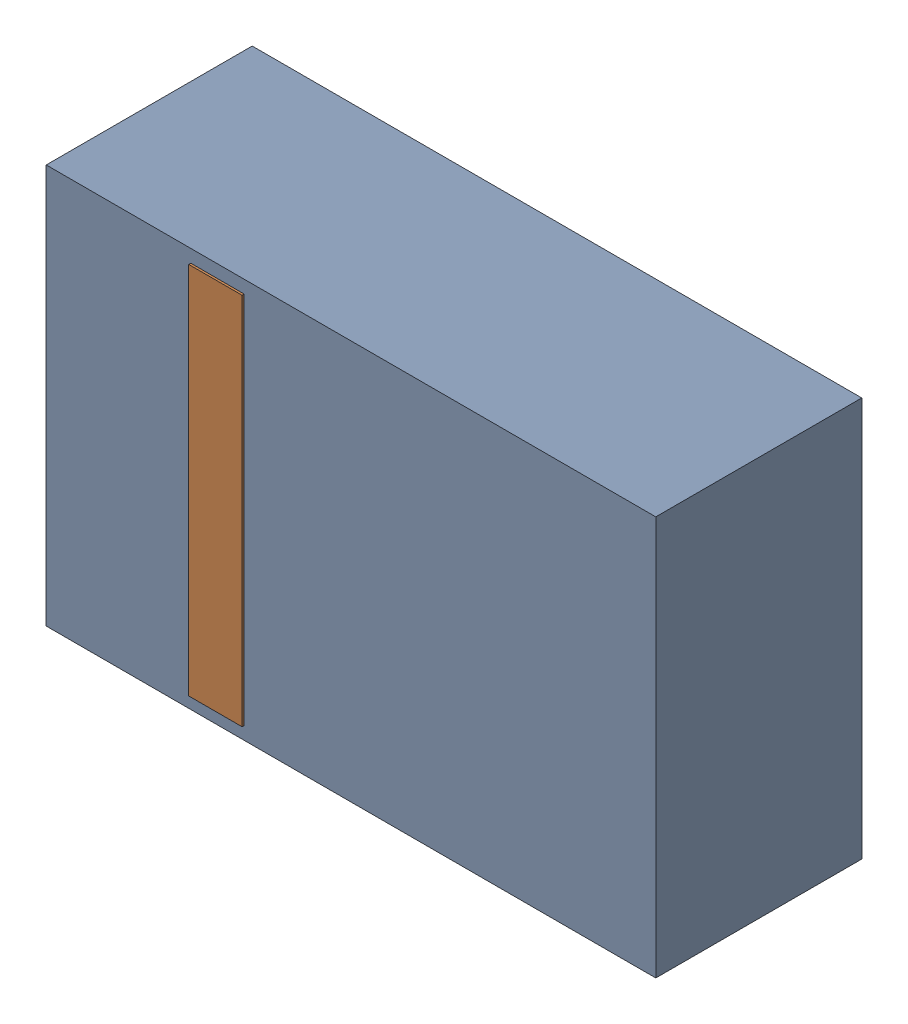
SolidWorks assembly D38, configuration Default. Lengths in mm.
Overall size (2.9 1.9 0.99).
4 component instances, 2 part files, 0 mates.
Components (placement in the parent):
- 905269392-1: 905269392 [Default] at (186.817 71.882 0) size (2.9 1.9 0.98)
  - Extruded_5-1: Extruded_5 [Default] at origin size (2.9 1.9 0.98)
- 905269800-1: 905269800 [Default] at (186.182 71.882 0.95) size (0.25 1.78 0.04)
  - Extruded_6-1: Extruded_6 [Default] at origin size (0.25 1.78 0.04)
